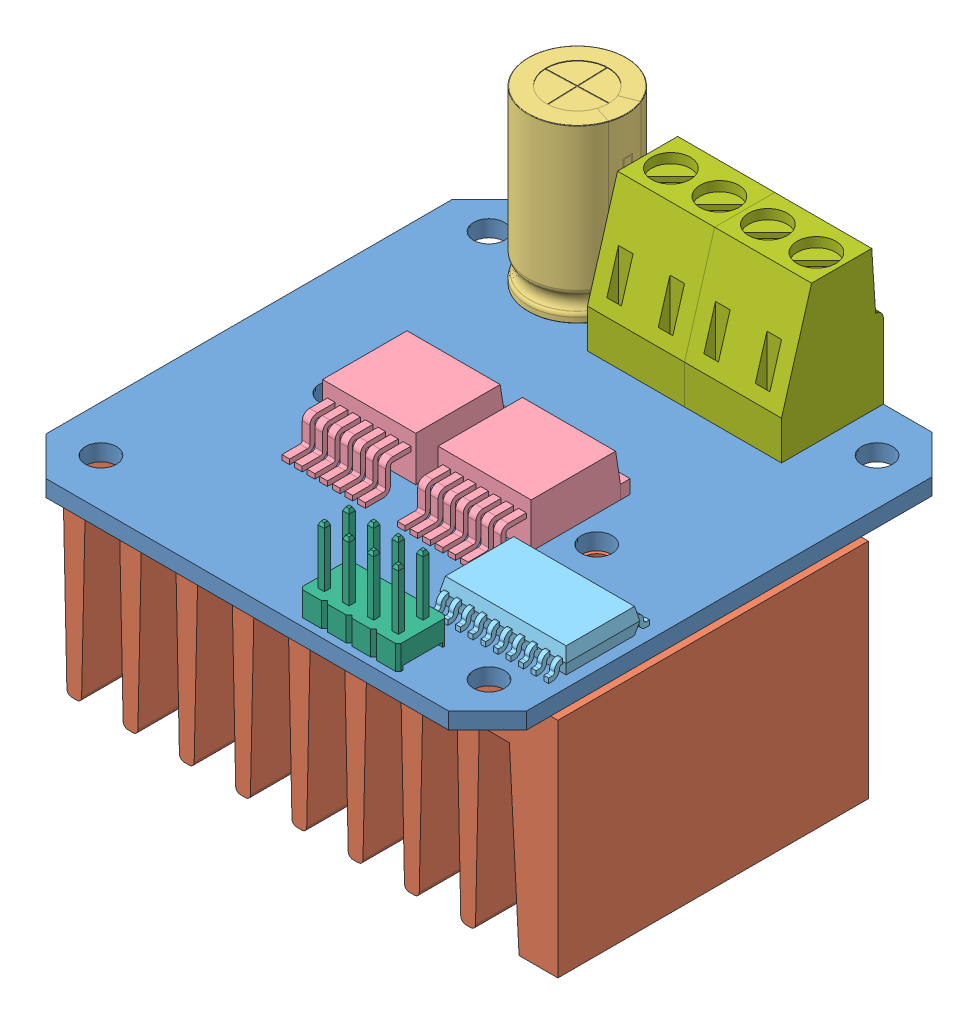
SolidWorks assembly BTS7960 43A HIGH POWER H BRIDGE MODULE, configuration Default. Lengths in mm.
Overall size (51 42.4 49.96).
9 component instances, 7 part files, 22 mates.
Components (placement in the parent):
- PCB, BTS7960 43A HIGH POWER H BRIDGE MODULE-1: PCB, BTS7960 43A HIGH POWER H BRIDGE MODULE [Default] at origin size (49.5 1.7 49.8)
- HEATSINK, BTS7960 43A HIGH POWER H BRIDGE MODULE-1: HEATSINK, BTS7960 43A HIGH POWER H BRIDGE MODULE [Default] at (0 0 2.4) size (51 23 32.02)
- ALUMINUM ELECTROLYTIC CAPACITOR, 330 uF, BTS7960 43A HIGH POWER H BRIDGE MODULE-1: ALUMINUM ELECTROLYTIC CAPACITOR, 330 uF, BTS7960 43A HIGH POWER H BRIDGE MODULE [Default] at (-10.75 1.8 -19.85) x (0.999469 0 -0.032584) z (0.032584 0 0.999469) size (10.1 18.7 10.1)
- BTN7960 IC, BTS7960 43A HIGH POWER H BRIDGE MODULE-1: BTN7960 IC, BTS7960 43A HIGH POWER H BRIDGE MODULE [Default] at (5.95 1.7 1.8) x (-1 0 0) z (0 0 -1) size (9.6 4.6 14.9)
- BTN7960 IC, BTS7960 43A HIGH POWER H BRIDGE MODULE-2: BTN7960 IC, BTS7960 43A HIGH POWER H BRIDGE MODULE [Default] at (-5.95 1.7 1.8) x (-1 0 0) z (0 0 -1) size (9.6 4.6 14.9)
- NXP 74HC244D, BUFFER AND LINE DRIVER, BTS7960 43A HIGH POWER H BRIDGE MODULE-1: NXP 74HC244D, BUFFER AND LINE DRIVER, BTS7960 43A HIGH POWER H BRIDGE MODULE [Default] at (17.35 3 12.1) size (13 2.6 10.4)
- 8 PIN HEADER, IC, BTS7960 43A HIGH POWER H BRIDGE MODULE-1: 8 PIN HEADER, IC, BTS7960 43A HIGH POWER H BRIDGE MODULE [Default] at (-34.78 4.2 20.29) x (0 0 -1) z (-1 0 0) size (5.08 11.6 10.16)
- EUROSTYLE TERMINAL BLOCK 2 POS 5.0 MM RA PLUG, BTS7960 43A HIGH POWER H BRIDGE MODULE-1: EUROSTYLE TERMINAL BLOCK 2 POS 5.0 MM RA PLUG, BTS7960 43A HIGH POWER H BRIDGE MODULE [Default] at (0.75 4.2 -6.5) size (10 14.5 10.5)
- EUROSTYLE TERMINAL BLOCK 2 POS 5.0 MM RA PLUG, BTS7960 43A HIGH POWER H BRIDGE MODULE-2: EUROSTYLE TERMINAL BLOCK 2 POS 5.0 MM RA PLUG, BTS7960 43A HIGH POWER H BRIDGE MODULE [Default] at (10.75 4.2 -6.5) size (10 14.5 10.5)
Mates (geometry in assembly coordinates):
- Coincident1: coordinate: point of PCB, BTS7960 43A HIGH POWER H BRIDGE MODULE-1; point of assembly
- Coincident2: coincident anti-aligned: plane of PCB, BTS7960 43A HIGH POWER H BRIDGE MODULE-1 through (0 0 0) normal (0 -1 0); plane of HEATSINK, BTS7960 43A HIGH POWER H BRIDGE MODULE-1 through (0 0 2.4) normal (0 1 0)
- Distance1: distance = 6.5 mm aligned: plane of HEATSINK, BTS7960 43A HIGH POWER H BRIDGE MODULE-1 through (-25.5 -4.5 18.4) normal (0 0 1); plane of PCB, BTS7960 43A HIGH POWER H BRIDGE MODULE-1 through (-24.75 1.7 24.9) normal (0 0 1)
- Coincident4: coincident anti-aligned: plane of PCB, BTS7960 43A HIGH POWER H BRIDGE MODULE-1 through (0 1.7 0) normal (0 1 0); plane of ALUMINUM ELECTROLYTIC CAPACITOR, 330 uF, BTS7960 43A HIGH POWER H BRIDGE MODULE-1 through (-10.75 1.7 -19.85) normal (0 -1 0)
- Distance2: distance = 14 mm: axis of ALUMINUM ELECTROLYTIC CAPACITOR, 330 uF, BTS7960 43A HIGH POWER H BRIDGE MODULE-1 through (-10.75 4.6983 -19.85) axis (0 1 0); plane of PCB, BTS7960 43A HIGH POWER H BRIDGE MODULE-1 through (-24.75 1.7 -24.9) normal (-1 0 0)
- Tangent1: tangent aligned: cylinder of ALUMINUM ELECTROLYTIC CAPACITOR, 330 uF, BTS7960 43A HIGH POWER H BRIDGE MODULE-1 through (-10.75 4.7 -19.85) axis (0 1 0) radius 5.05; plane of PCB, BTS7960 43A HIGH POWER H BRIDGE MODULE-1 through (-24.75 1.7 -24.9) normal (0 0 -1)
- Coincident5: coincident anti-aligned: plane of PCB, BTS7960 43A HIGH POWER H BRIDGE MODULE-1 through (0 1.7 0) normal (0 1 0); plane of BTN7960 IC, BTS7960 43A HIGH POWER H BRIDGE MODULE-1 through (1.15 1.7 -2.8) normal (0 -1 0)
- Coincident6: coincident aligned: plane of HEATSINK, BTS7960 43A HIGH POWER H BRIDGE MODULE-1 through (0 0 2.4) normal (1 0 0); plane of assembly through (0 0 0) normal (1 0 0)
- Distance4: distance = 14 mm aligned: plane of BTN7960 IC, BTS7960 43A HIGH POWER H BRIDGE MODULE-1 through (10.75 1.7 1.8) normal (1 0 0); plane of PCB, BTS7960 43A HIGH POWER H BRIDGE MODULE-1 through (24.75 1.7 -24.9) normal (1 0 0)
- Coincident7: coincident anti-aligned: plane of PCB, BTS7960 43A HIGH POWER H BRIDGE MODULE-1 through (0 1.7 0) normal (0 1 0); plane of NXP 74HC244D, BUFFER AND LINE DRIVER, BTS7960 43A HIGH POWER H BRIDGE MODULE-1 through (17.35 1.7 12.1) normal (0 -1 0)
- Distance5: distance = 0.9 mm: plane of PCB, BTS7960 43A HIGH POWER H BRIDGE MODULE-1 through (24.75 1.7 -24.9) normal (1 0 0); line of NXP 74HC244D, BUFFER AND LINE DRIVER, BTS7960 43A HIGH POWER H BRIDGE MODULE-1 through (23.85 3 15.9) axis (0 0 -1)
- Distance6: distance = 9 mm: plane of PCB, BTS7960 43A HIGH POWER H BRIDGE MODULE-1 through (-24.75 1.7 24.9) normal (0 0 1); line of NXP 74HC244D, BUFFER AND LINE DRIVER, BTS7960 43A HIGH POWER H BRIDGE MODULE-1 through (10.85 3 15.9) axis (1 0 0)
- Coincident8: coincident anti-aligned: plane of PCB, BTS7960 43A HIGH POWER H BRIDGE MODULE-1 through (0 1.7 0) normal (0 1 0); plane of 8 PIN HEADER, IC, BTS7960 43A HIGH POWER H BRIDGE MODULE-1 through (-34.78 1.7 22.53) normal (0 -1 0)
- Distance7: distance = 0.8 mm aligned: plane of 8 PIN HEADER, IC, BTS7960 43A HIGH POWER H BRIDGE MODULE-1 through (12.51 1.7 24.1) normal (0 0 1); plane of PCB, BTS7960 43A HIGH POWER H BRIDGE MODULE-1 through (-24.75 1.7 24.9) normal (0 0 1)
- Distance8: distance = 10 mm aligned: plane of 8 PIN HEADER, IC, BTS7960 43A HIGH POWER H BRIDGE MODULE-1 through (14.75 1.7 23.8) normal (1 0 0); plane of PCB, BTS7960 43A HIGH POWER H BRIDGE MODULE-1 through (24.75 1.7 -24.9) normal (1 0 0)
- Distance9: distance = 18.5 mm aligned: plane of BTN7960 IC, BTS7960 43A HIGH POWER H BRIDGE MODULE-2 through (-10.75 1.7 6.4) normal (0 0 1); plane of PCB, BTS7960 43A HIGH POWER H BRIDGE MODULE-1 through (-24.75 1.7 24.9) normal (0 0 1)
- Coincident9: coincident anti-aligned: plane of EUROSTYLE TERMINAL BLOCK 2 POS 5.0 MM RA PLUG, BTS7960 43A HIGH POWER H BRIDGE MODULE-1 through (5.75 4.2 -6.5) normal (1 0 0); plane of EUROSTYLE TERMINAL BLOCK 2 POS 5.0 MM RA PLUG, BTS7960 43A HIGH POWER H BRIDGE MODULE-2 through (5.75 4.2 -6.5) normal (-1 0 0)
- Coincident10: coincident aligned: plane of EUROSTYLE TERMINAL BLOCK 2 POS 5.0 MM RA PLUG, BTS7960 43A HIGH POWER H BRIDGE MODULE-1 through (-4.25 16.2 -24.3) normal (0 1 0); plane of EUROSTYLE TERMINAL BLOCK 2 POS 5.0 MM RA PLUG, BTS7960 43A HIGH POWER H BRIDGE MODULE-2 through (5.75 16.2 -24.3) normal (0 1 0)
- Coincident11: coincident aligned: plane of EUROSTYLE TERMINAL BLOCK 2 POS 5.0 MM RA PLUG, BTS7960 43A HIGH POWER H BRIDGE MODULE-1 through (20.7146 5.7 -14.4) normal (0 0 1); plane of EUROSTYLE TERMINAL BLOCK 2 POS 5.0 MM RA PLUG, BTS7960 43A HIGH POWER H BRIDGE MODULE-2 through (30.7146 5.7 -14.4) normal (0 0 1)
- Coincident12: coincident anti-aligned: plane of PCB, BTS7960 43A HIGH POWER H BRIDGE MODULE-1 through (0 1.7 0) normal (0 1 0); plane of EUROSTYLE TERMINAL BLOCK 2 POS 5.0 MM RA PLUG, BTS7960 43A HIGH POWER H BRIDGE MODULE-2 through (10.75 1.7 -6.5) normal (0 -1 0)
- Coincident13: coincident aligned: plane of PCB, BTS7960 43A HIGH POWER H BRIDGE MODULE-1 through (-24.75 1.7 -24.9) normal (0 0 -1); plane of EUROSTYLE TERMINAL BLOCK 2 POS 5.0 MM RA PLUG, BTS7960 43A HIGH POWER H BRIDGE MODULE-2 through (5.75 0.7 -24.9) normal (0 0 -1)
- Distance10: distance = 9 mm aligned: plane of EUROSTYLE TERMINAL BLOCK 2 POS 5.0 MM RA PLUG, BTS7960 43A HIGH POWER H BRIDGE MODULE-2 through (15.75 4.2 -6.5) normal (1 0 0); plane of PCB, BTS7960 43A HIGH POWER H BRIDGE MODULE-1 through (24.75 1.7 -24.9) normal (1 0 0)
